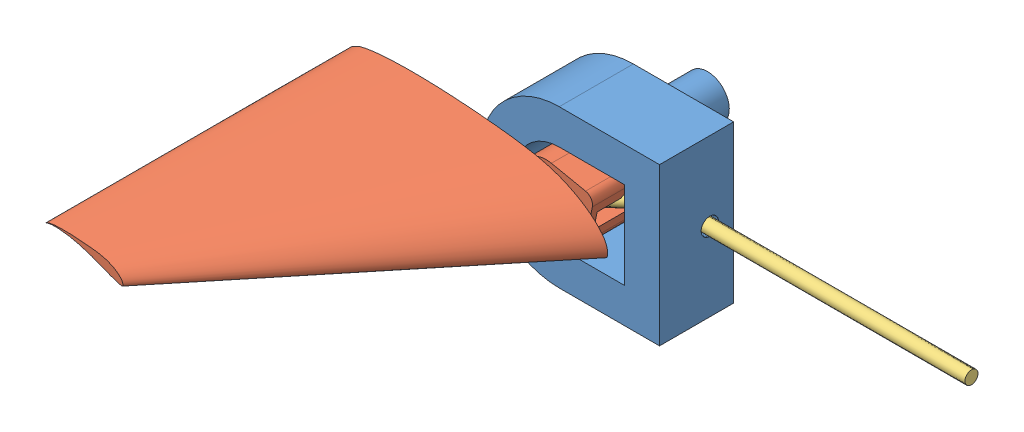
SolidWorks assembly RDS, configuration Default. Lengths in mm.
Overall size (131.34 36 107.05).
3 component instances, 3 part files, 4 mates.
Components (placement in the parent):
- TestSocket-1: TestSocket [Default] at (8.8479 31.7451 30.0277) x (-1 0 0) z (0 1 0) size (41 37 36)
- pecRnew-1: pecRnew [Default] at (19.9382 25.7901 45.0277) x (-0.979574 0.201085 0) z (0 0 -1) size (60.12 12 100.05)
- Rod-1: Rod [Default] at (91.8479 31.7451 33.4977) x (1 0 0) z (0 0.26698 -0.963702) size (82.87 3 9.8)
Mates (geometry in assembly coordinates):
- Concentric1: concentric: cylinder of TestSocket-1 through (5.8479 31.7451 45.0277) axis (0 0 -1) radius 3; cylinder of pecRnew-1 through (5.8479 31.7451 15.0277) axis (0 0 1) radius 3
- Coincident1: coincident: plane of TestSocket-1 through (8.8479 31.7451 30.0277) normal (0 0 1); plane of pecRnew-1 through (5.8479 31.7451 30.0277) normal (0 0 -1)
- Concentric2: concentric: cylinder of TestSocket-1 through (11.8479 31.7451 33.4977) axis (1 0 0) radius 2; cylinder of Rod-1 through (91.8479 31.7451 33.4977) axis (-1 0 0) radius 1.5
- Distance1: distance = 60 mm: plane of TestSocket-1 through (31.8479 13.7451 45.0277) normal (1 0 0); plane of Rod-1 through (91.8479 31.7451 33.4977) normal (1 0 0)
